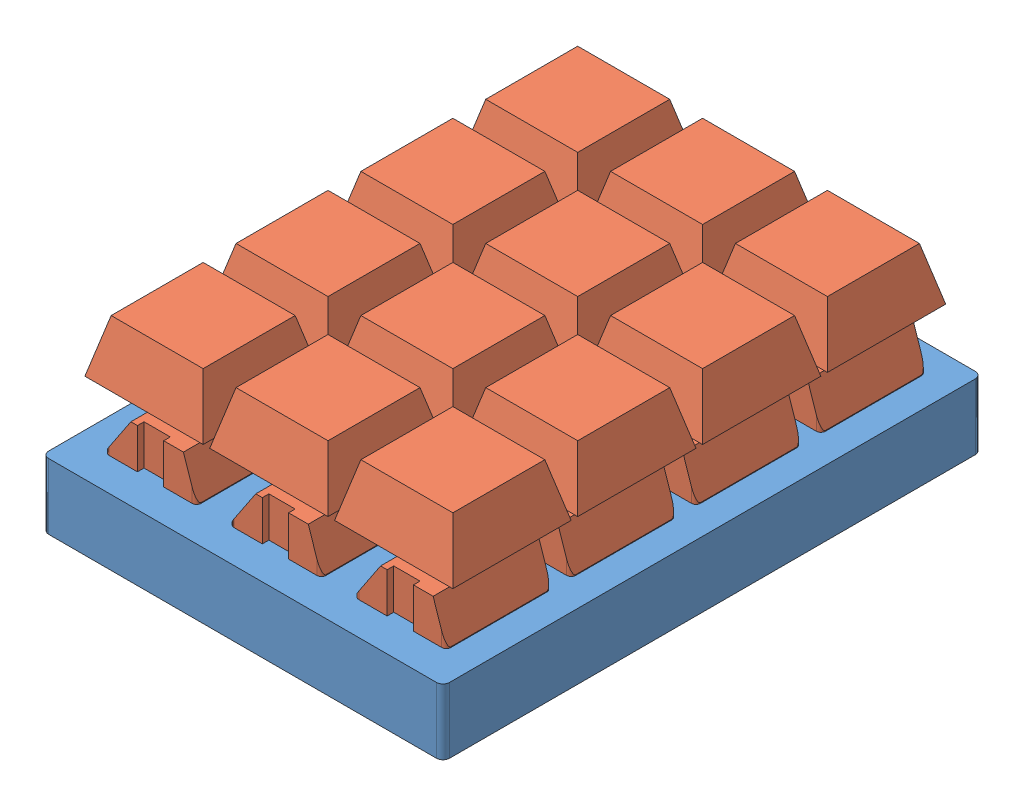
SolidWorks assembly keyboard, configuration Default. Lengths in mm.
Overall size (62 27.6 82).
13 component instances, 2 part files, 36 mates.
Components (placement in the parent):
- plaque clavier-1: plaque clavier [Default] at (44.0589 62.8359 29.1766) size (62 10 82)
- key-1: key [Default] at (25.0589 67.9359 57.1766) size (18 22.5 18)
- key-2: key [Default] at (44.0589 67.9359 57.1766) size (18 22.5 18)
- key-3: key [Default] at (63.0589 67.9359 57.1766) size (18 22.5 18)
- key-4: key [Default] at (25.0589 67.9359 38.1766) size (18 22.5 18)
- key-5: key [Default] at (44.0589 67.9359 38.1766) size (18 22.5 18)
- key-6: key [Default] at (63.0589 67.9359 38.1766) size (18 22.5 18)
- key-7: key [Default] at (25.0589 67.9359 19.1766) size (18 22.5 18)
- key-8: key [Default] at (44.0589 67.9359 19.1766) size (18 22.5 18)
- key-9: key [Default] at (63.0589 67.9359 19.1766) size (18 22.5 18)
- key-10: key [Default] at (44.0589 67.9359 0.1766) size (18 22.5 18)
- key-11: key [Default] at (25.0589 67.9359 0.1766) size (18 22.5 18)
- key-12: key [Default] at (63.0589 67.9359 0.1766) size (18 22.5 18)
Mates (geometry in assembly coordinates):
- Coincident1: coincident anti-aligned: plane of plaque clavier-1 through (18.7589 62.8359 65.1766) normal (0 0 -1); plane of key-1 through (18.7589 78.9359 65.1766) normal (0 0 1)
- Coincident2: coincident anti-aligned: plane of plaque clavier-1 through (18.0589 62.8359 49.8766) normal (1 0 0); plane of key-1 through (18.0589 78.9359 64.4766) normal (-1 0 0)
- Coincident3: coincident anti-aligned: plane of plaque clavier-1 through (44.0589 72.8359 29.1766) normal (0 1 0); plane of key-1 through (17.9589 72.8359 64.4766) normal (0 -1 0)
- Coincident5: coincident anti-aligned: plane of plaque clavier-1 through (37.7589 62.8359 49.1766) normal (0 0 1); plane of key-2 through (37.7589 78.9359 49.1766) normal (0 0 -1)
- Coincident6: coincident anti-aligned: plane of plaque clavier-1 through (37.0589 62.8359 49.8766) normal (1 0 0); plane of key-2 through (37.0589 78.9359 64.4766) normal (-1 0 0)
- Coincident7: coincident anti-aligned: plane of plaque clavier-1 through (44.0589 72.8359 29.1766) normal (0 1 0); plane of key-2 through (36.9589 72.8359 64.4766) normal (0 -1 0)
- Coincident9: coincident anti-aligned: plane of plaque clavier-1 through (56.7589 62.8359 65.1766) normal (0 0 -1); plane of key-3 through (56.7589 78.9359 65.1766) normal (0 0 1)
- Coincident10: coincident anti-aligned: plane of plaque clavier-1 through (56.0589 62.8359 49.8766) normal (1 0 0); plane of key-3 through (56.0589 78.9359 64.4766) normal (-1 0 0)
- Coincident11: coincident anti-aligned: plane of plaque clavier-1 through (44.0589 72.8359 29.1766) normal (0 1 0); plane of key-3 through (55.9589 72.8359 64.4766) normal (0 -1 0)
- Coincident13: coincident anti-aligned: plane of plaque clavier-1 through (18.7589 62.8359 46.1766) normal (0 0 -1); plane of key-4 through (18.7589 78.9359 46.1766) normal (0 0 1)
- Coincident14: coincident anti-aligned: plane of plaque clavier-1 through (46.0589 62.8359 46.1766) normal (0 0 -1); plane of key-5 through (37.7589 78.9359 46.1766) normal (0 0 1)
- Coincident15: coincident anti-aligned: plane of plaque clavier-1 through (37.0589 62.8359 30.8766) normal (1 0 0); plane of key-5 through (37.0589 78.9359 45.4766) normal (-1 0 0)
- Coincident16: coincident anti-aligned: plane of plaque clavier-1 through (56.0589 62.8359 30.8766) normal (1 0 0); plane of key-6 through (56.0589 78.9359 45.4766) normal (-1 0 0)
- Coincident17: coincident anti-aligned: plane of plaque clavier-1 through (65.0589 62.8359 46.1766) normal (0 0 -1); plane of key-6 through (65.0589 78.9359 46.1766) normal (0 0 1)
- Coincident18: coincident anti-aligned: plane of plaque clavier-1 through (70.0589 62.8359 11.8766) normal (-1 0 0); plane of key-9 through (70.0589 78.9359 26.4766) normal (1 0 0)
- Coincident21: coincident anti-aligned: plane of plaque clavier-1 through (18.0589 62.8359 30.8766) normal (1 0 0); plane of key-4 through (18.0589 78.9359 45.4766) normal (-1 0 0)
- Coincident22: coincident anti-aligned: plane of plaque clavier-1 through (18.0589 62.8359 11.8766) normal (1 0 0); plane of key-7 through (18.0589 78.9359 26.4766) normal (-1 0 0)
- Coincident23: coincident anti-aligned: plane of plaque clavier-1 through (18.7589 62.8359 27.1766) normal (0 0 -1); plane of key-7 through (18.7589 78.9359 27.1766) normal (0 0 1)
- Coincident27: coincident anti-aligned: plane of plaque clavier-1 through (37.0589 62.8359 11.8766) normal (1 0 0); plane of key-8 through (37.0589 78.9359 26.4766) normal (-1 0 0)
- Coincident28: coincident anti-aligned: plane of plaque clavier-1 through (46.0589 62.8359 27.1766) normal (0 0 -1); plane of key-8 through (46.0589 78.9359 27.1766) normal (0 0 1)
- Coincident30: coincident anti-aligned: plane of plaque clavier-1 through (65.0589 62.8359 27.1766) normal (0 0 -1); plane of key-9 through (65.0589 78.9359 27.1766) normal (0 0 1)
- Coincident31: coincident anti-aligned: plane of plaque clavier-1 through (65.0589 62.8359 8.1766) normal (0 0 -1); plane of key-12 through (65.0589 78.9359 8.1766) normal (0 0 1)
- Coincident32: coincident anti-aligned: plane of plaque clavier-1 through (56.0589 62.8359 -7.1234) normal (1 0 0); plane of key-12 through (56.0589 78.9359 7.4766) normal (-1 0 0)
- Coincident33: coincident anti-aligned: plane of plaque clavier-1 through (37.0589 62.8359 -7.1234) normal (1 0 0); plane of key-10 through (37.0589 78.9359 7.4766) normal (-1 0 0)
- Coincident34: coincident anti-aligned: plane of plaque clavier-1 through (37.7589 62.8359 -7.8234) normal (0 0 1); plane of key-10 through (37.7589 78.9359 -7.8234) normal (0 0 -1)
- Coincident35: coincident anti-aligned: plane of plaque clavier-1 through (18.0589 62.8359 -7.1234) normal (1 0 0); plane of key-11 through (18.0589 78.9359 7.4766) normal (-1 0 0)
- Coincident36: coincident anti-aligned: plane of plaque clavier-1 through (27.0589 62.8359 -7.8234) normal (0 0 1); plane of key-11 through (27.0589 78.9359 -7.8234) normal (0 0 -1)
- Coincident38: coincident anti-aligned: plane of plaque clavier-1 through (44.0589 72.8359 29.1766) normal (0 1 0); plane of key-11 through (17.9589 72.8359 7.4766) normal (0 -1 0)
- Coincident39: coincident anti-aligned: plane of plaque clavier-1 through (44.0589 72.8359 29.1766) normal (0 1 0); plane of key-10 through (36.9589 72.8359 7.4766) normal (0 -1 0)
- Coincident40: coincident anti-aligned: plane of plaque clavier-1 through (44.0589 72.8359 29.1766) normal (0 1 0); plane of key-12 through (55.9589 72.8359 7.4766) normal (0 -1 0)
- Coincident41: coincident anti-aligned: plane of plaque clavier-1 through (44.0589 72.8359 29.1766) normal (0 1 0); plane of key-9 through (55.9589 72.8359 26.4766) normal (0 -1 0)
- Coincident42: coincident anti-aligned: plane of plaque clavier-1 through (44.0589 72.8359 29.1766) normal (0 1 0); plane of key-5 through (36.9589 72.8359 45.4766) normal (0 -1 0)
- Coincident43: coincident anti-aligned: plane of plaque clavier-1 through (44.0589 72.8359 29.1766) normal (0 1 0); plane of key-7 through (17.9589 72.8359 26.4766) normal (0 -1 0)
- Coincident44: coincident anti-aligned: plane of plaque clavier-1 through (44.0589 72.8359 29.1766) normal (0 1 0); plane of key-8 through (36.9589 72.8359 26.4766) normal (0 -1 0)
- Coincident45: coincident anti-aligned: plane of plaque clavier-1 through (44.0589 72.8359 29.1766) normal (0 1 0); plane of key-4 through (17.9589 72.8359 45.4766) normal (0 -1 0)
- Coincident46: coincident anti-aligned: plane of plaque clavier-1 through (44.0589 72.8359 29.1766) normal (0 1 0); plane of key-6 through (55.9589 72.8359 45.4766) normal (0 -1 0)
